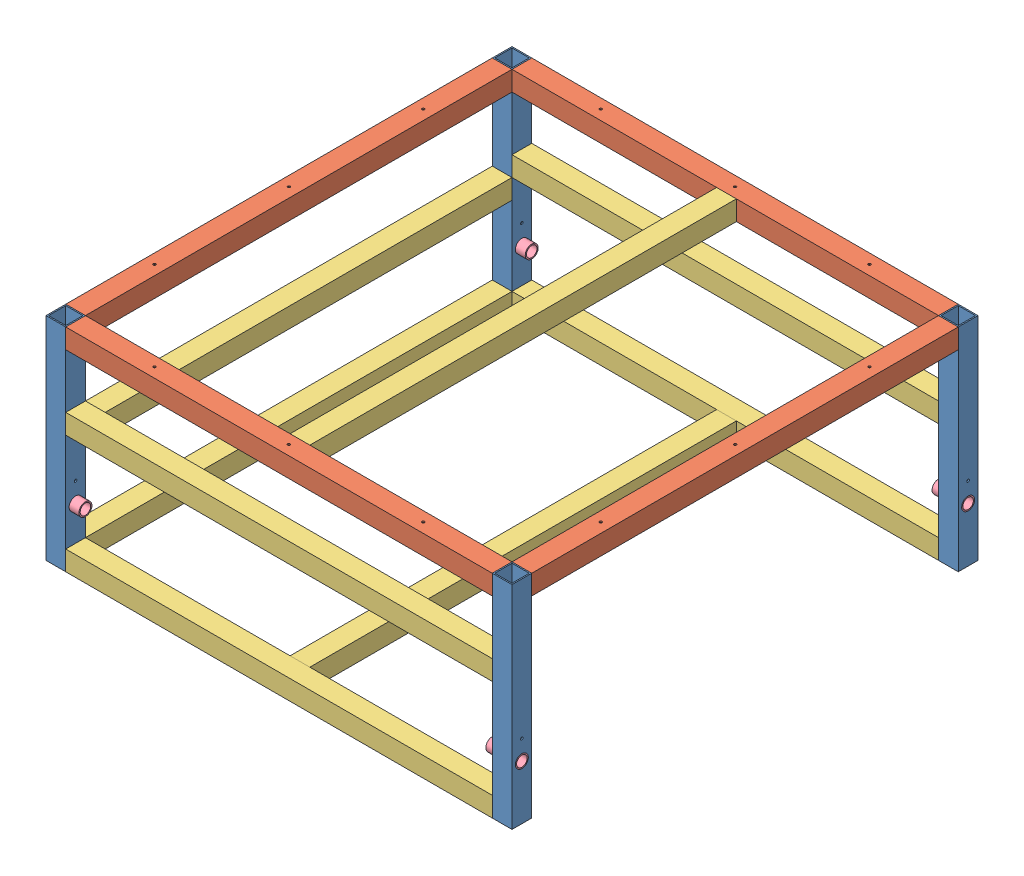
SolidWorks assembly GE-19030, configuration Default. Lengths in mm.
Overall size (1200.15 546.1 1200.15).
20 component instances, 4 part files, 58 mates.
Components (placement in the parent):
- GE-19030-02-1: GE-19030-02 [Default] at (-409.852 -285.75 461.6211) x (-1 0 0) z (0 0 -1) size (50.8 546.1 50.8)
- GE-19030-02-2: GE-19030-02 [Default] at (-409.852 -285.75 1610.9711) x (-1 0 0) z (0 0 -1) size (50.8 546.1 50.8)
- GE-19030-01-2: GE-19030-01 [Default] at (-409.852 -38.1 1036.2961) x (-1 0 0) z (0 0 1) size (50.8 50.8 1098.55)
- GE-19030-01-4: GE-19030-01 [Default] at (-1009.927 -38.1 1636.3711) x (0 0 -1) z (1 0 0) size (50.8 50.8 1098.55)
- GE-19030-01-5: GE-19030-01 [Default] at (-1009.927 -38.1 436.2211) x (0 0 1) z (1 0 0) size (50.8 50.8 1098.55)
- GE-19030-01-9: GE-19030-01 [Default] at (-1610.002 -38.1 1036.2961) size (50.8 50.8 1098.55)
- GE-19030-02-5: GE-19030-02 [Default] at (-1610.002 -285.75 1610.9711) size (50.8 546.1 50.8)
- GE-19030-02-6: GE-19030-02 [Default] at (-1610.002 -285.75 461.6211) size (50.8 546.1 50.8)
- GE-19030-03-5: GE-19030-03 [Default] at (-1584.602 -279.4 487.0211) size (50.8 50.8 1098.55)
- GE-19030-03-6: GE-19030-03 [Default] at (-1006.752 -38.1 487.0211) size (50.8 50.8 1098.55)
- GE-19030-04-1: GE-19030-04 [Default] at (-1610.002 -419.1 1610.9711) x (0 -0.791316 0.611408) z (1 0 0) size (33.4 33.4 76.2)
- GE-19030-04-2: GE-19030-04 [Default] at (-1610.002 -419.1 461.6211) x (0 0 1) z (1 0 0) size (33.4 33.4 76.2)
- GE-19030-04-3: GE-19030-04 [Default] at (-409.852 -419.1 461.6211) x (0 0.9686 0.248623) z (-1 0 0) size (33.4 33.4 76.2)
- GE-19030-04-4: GE-19030-04 [Default] at (-409.852 -419.1 1610.9711) x (0 -0.03489 -0.999391) z (-1 0 0) size (33.4 33.4 76.2)
- GE-19030-03-7: GE-19030-03 [Default] at (-1559.202 -228.6 1610.9711) x (0 0 -1) z (1 0 0) size (50.8 50.8 1098.55)
- GE-19030-03-8: GE-19030-03 [Default] at (-1559.202 -228.6 461.6211) x (0 0 -1) z (1 0 0) size (50.8 50.8 1098.55)
- GE-19030-03-9: GE-19030-03 [Default] at (-1584.602 -533.4 487.0211) size (50.8 50.8 1098.55)
- GE-19030-03-10: GE-19030-03 [Default] at (-1559.202 -533.4 1610.9711) x (0 0 -1) z (1 0 0) size (50.8 50.8 1098.55)
- GE-19030-03-11: GE-19030-03 [Default] at (-1559.202 -533.4 461.6211) x (0 0 -1) z (1 0 0) size (50.8 50.8 1098.55)
- GE-19030-03-12: GE-19030-03 [Default] at (-1006.752 -533.4 487.0211) size (50.8 50.8 1098.55)
Mates (geometry in assembly coordinates):
- Coincident56: coincident: plane of GE-19030-01-4 through (-1559.202 -12.7 1585.5711) normal (-1 0 0); plane of GE-19030-02-5 through (-1559.202 -285.75 1610.9711) normal (1 0 0)
- Coincident57: coincident: plane of GE-19030-01-4 through (-1009.927 -38.1 1636.3711) normal (0 0 1); plane of GE-19030-02-5 through (-1559.202 -558.8 1636.3711) normal (0 0 1)
- Coincident58: coincident: plane of GE-19030-01-4 through (-460.652 -12.7 1585.5711) normal (0 1 0); plane of GE-19030-02-5 through (-1559.202 -12.7 1585.5711) normal (0 1 0)
- Coincident85: coincident: plane of GE-19030-01-9 through (-1559.202 -12.7 1585.5711) normal (0 0 1); plane of GE-19030-02-5 through (-1559.202 -558.8 1585.5711) normal (0 0 -1)
- Coincident86: coincident: plane of GE-19030-01-9 through (-1610.002 -38.1 1036.2961) normal (-1 0 0); plane of GE-19030-02-5 through (-1610.002 -285.75 1610.9711) normal (-1 0 0)
- Coincident87: coincident: plane of GE-19030-01-4 through (-460.652 -12.7 1585.5711) normal (0 1 0); plane of GE-19030-01-9 through (-1559.202 -12.7 1585.5711) normal (0 1 0)
- Coincident111: coincident: plane of GE-19030-02-6 through (-1610.002 -285.75 461.6211) normal (-1 0 0); plane of GE-19030-03-5 through (-1610.002 -304.8 1585.5711) normal (-1 0 0)
- Coincident112: coincident: plane of GE-19030-02-6 through (-1559.202 -558.8 487.0211) normal (0 0 1); plane of GE-19030-03-5 through (-1584.602 -279.4 487.0211) normal (0 0 -1)
- Coincident124: coincident: plane of GE-19030-01-9 through (-1610.002 -38.1 1036.2961) normal (-1 0 0); plane of GE-19030-02-6 through (-1610.002 -285.75 461.6211) normal (-1 0 0)
- Concentric5: concentric: cylinder of GE-19030-02-1 through (-409.852 -419.1 461.6211) axis (-1 0 0) radius 16.7005; cylinder of GE-19030-04-3 through (-486.052 -419.1 461.6211) axis (1 0 0) radius 16.7005
- Coincident131: coincident: plane of GE-19030-02-1 through (-409.852 -285.75 461.6211) normal (1 0 0); plane of GE-19030-04-3 through (-409.852 -419.1 461.6211) normal (1 0 0)
- Concentric6: concentric: cylinder of GE-19030-02-6 through (-1610.002 -419.1 461.6211) axis (1 0 0) radius 16.7005; cylinder of GE-19030-04-2 through (-1533.802 -419.1 461.6211) axis (-1 0 0) radius 16.7005
- Coincident132: coincident: circle of GE-19030-02-6; circle of GE-19030-04-2
- Concentric7: concentric: cylinder of GE-19030-02-5 through (-1610.002 -419.1 1610.9711) axis (1 0 0) radius 16.7005; cylinder of GE-19030-04-1 through (-1533.802 -419.1 1610.9711) axis (-1 0 0) radius 16.7005
- Coincident133: coincident: plane of GE-19030-02-5 through (-1610.002 -285.75 1610.9711) normal (-1 0 0); plane of GE-19030-04-1 through (-1610.002 -419.1 1610.9711) normal (-1 0 0)
- Concentric8: concentric: cylinder of GE-19030-02-2 through (-409.852 -419.1 1610.9711) axis (-1 0 0) radius 16.7005; cylinder of GE-19030-04-4 through (-486.052 -419.1 1610.9711) axis (1 0 0) radius 16.7005
- Coincident134: coincident: plane of GE-19030-02-2 through (-409.852 -285.75 1610.9711) normal (1 0 0); plane of GE-19030-04-4 through (-409.852 -419.1 1610.9711) normal (1 0 0)
- Coincident147: coincident: plane of GE-19030-02-2 through (-460.652 -285.75 1610.9711) normal (-1 0 0); plane of GE-19030-03-7 through (-460.652 -228.6 1610.9711) normal (1 0 0)
- Coincident151: coincident: plane of GE-19030-02-5 through (-1559.202 -558.8 1636.3711) normal (0 0 1); plane of GE-19030-03-7 through (-460.652 -254 1636.3711) normal (0 0 1)
- Coincident152: coincident: plane of GE-19030-03-5 through (-1559.202 -254 1585.5711) normal (0 1 0); plane of GE-19030-03-7 through (-460.652 -254 1585.5711) normal (0 -1 0)
- Coincident153: coincident: plane of GE-19030-02-6 through (-1559.202 -285.75 461.6211) normal (1 0 0); plane of GE-19030-03-8 through (-1559.202 -228.6 461.6211) normal (-1 0 0)
- Coincident154: coincident: plane of GE-19030-02-6 through (-1559.202 -558.8 436.2211) normal (0 0 -1); plane of GE-19030-03-8 through (-460.652 -254 436.2211) normal (0 0 -1)
- Coincident155: coincident: plane of GE-19030-03-5 through (-1559.202 -254 1585.5711) normal (0 1 0); plane of GE-19030-03-8 through (-460.652 -254 436.2211) normal (0 -1 0)
- Parallel2: parallel: plane of GE-19030-02-2 through (-409.852 -285.75 1610.9711) normal (1 0 0); plane of GE-19030-01-2 through (-409.852 -38.1 1036.2961) normal (1 0 0)
- Coincident165: coincident: plane of GE-19030-02-1 through (-409.852 -285.75 461.6211) normal (1 0 0); plane of GE-19030-01-2 through (-409.852 -38.1 1036.2961) normal (1 0 0)
- Distance13: distance = 520.7 mm: plane of GE-19030-01-2 through (-460.652 -38.1 1036.2961) normal (-1 0 0); plane of GE-19030-03-6 through (-981.352 -63.5 1585.5711) normal (1 0 0)
- Coincident168: coincident: plane of GE-19030-01-9 through (-1559.202 -12.7 487.0211) normal (0 0 -1); plane of GE-19030-02-6 through (-1559.202 -558.8 487.0211) normal (0 0 1)
- Coincident174: coincident: line of GE-19030-02-1; line of GE-19030-01-5 through (-460.652 -12.7 487.0211) axis (0 0 -1)
- Coincident175: coincident: line of GE-19030-02-6 through (-1610.002 -12.7 487.0211) axis (0 -1 0); plane of GE-19030-03-9 through (-1584.602 -533.4 487.0211) normal (0 0 -1)
- Coincident176: coincident: plane of GE-19030-02-6 through (-1610.002 -285.75 461.6211) normal (-1 0 0); plane of GE-19030-03-9 through (-1610.002 -558.8 1585.5711) normal (-1 0 0)
- Coincident177: coincident: plane of GE-19030-02-6 through (-1559.202 -558.8 436.2211) normal (0 -1 0); plane of GE-19030-03-9 through (-1559.202 -558.8 1585.5711) normal (0 -1 0)
- Coincident178: coincident: plane of GE-19030-02-5 through (-1559.202 -285.75 1610.9711) normal (1 0 0); plane of GE-19030-03-10 through (-1559.202 -533.4 1610.9711) normal (-1 0 0)
- Coincident179: coincident: plane of GE-19030-03-9 through (-1559.202 -558.8 1585.5711) normal (0 -1 0); plane of GE-19030-03-10 through (-460.652 -558.8 1585.5711) normal (0 -1 0)
- Coincident180: coincident: plane of GE-19030-02-5 through (-1559.202 -558.8 1636.3711) normal (0 0 1); plane of GE-19030-03-10 through (-460.652 -558.8 1636.3711) normal (0 0 1)
- Coincident181: coincident: plane of GE-19030-02-6 through (-1559.202 -285.75 461.6211) normal (1 0 0); plane of GE-19030-03-11 through (-1559.202 -533.4 461.6211) normal (-1 0 0)
- Coincident182: coincident: plane of GE-19030-02-6 through (-1559.202 -558.8 436.2211) normal (0 -1 0); plane of GE-19030-03-11 through (-460.652 -558.8 436.2211) normal (0 -1 0)
- Coincident183: coincident: plane of GE-19030-02-6 through (-1559.202 -558.8 436.2211) normal (0 0 -1); plane of GE-19030-03-11 through (-460.652 -558.8 436.2211) normal (0 0 -1)
- Coincident188: coincident: plane of GE-19030-02-1 through (-460.652 -285.75 461.6211) normal (-1 0 0); plane of GE-19030-03-11 through (-460.652 -533.4 461.6211) normal (1 0 0)
- Coincident191: coincident: plane of GE-19030-01-5 through (-460.652 -12.7 487.0211) normal (0 1 0); plane of GE-19030-02-6 through (-1559.202 -12.7 436.2211) normal (0 1 0)
- Coincident192: coincident: plane of GE-19030-01-5 through (-1009.927 -38.1 436.2211) normal (0 0 -1); plane of GE-19030-02-6 through (-1559.202 -558.8 436.2211) normal (0 0 -1)
- Coincident193: coincident: plane of GE-19030-02-1 through (-460.652 -558.8 436.2211) normal (0 0 -1); plane of GE-19030-01-5 through (-1009.927 -38.1 436.2211) normal (0 0 -1)
- Coincident194: coincident: plane of GE-19030-02-1 through (-460.652 -558.8 487.0211) normal (0 0 1); line of GE-19030-01-2 through (-413.027 -15.875 487.0211) axis (-1 0 0)
- Coincident195: coincident: plane of GE-19030-02-1 through (-460.652 -12.7 487.0211) normal (0 1 0); plane of GE-19030-01-2 through (-460.652 -12.7 1585.5711) normal (0 1 0)
- Coincident196: coincident: plane of GE-19030-01-9 through (-1559.202 -12.7 1585.5711) normal (0 1 0); plane of GE-19030-02-6 through (-1559.202 -12.7 436.2211) normal (0 1 0)
- Coincident197: coincident: plane of GE-19030-02-2 through (-460.652 -285.75 1610.9711) normal (-1 0 0); plane of GE-19030-01-4 through (-460.652 -12.7 1585.5711) normal (1 0 0)
- Coincident198: coincident: plane of GE-19030-02-2 through (-460.652 -558.8 1585.5711) normal (0 0 -1); plane of GE-19030-01-2 through (-460.652 -63.5 1585.5711) normal (0 0 1)
- Coincident199: coincident: plane of GE-19030-02-2 through (-460.652 -558.8 1636.3711) normal (0 -1 0); plane of GE-19030-03-10 through (-460.652 -558.8 1585.5711) normal (0 -1 0)
- Distance14: distance = 254 mm: plane of GE-19030-03-8 through (-460.652 -254 436.2211) normal (0 -1 0); plane of GE-19030-03-11 through (-460.652 -508 436.2211) normal (0 1 0)
- Coincident201: coincident: plane of GE-19030-01-5 through (-1009.927 -38.1 487.0211) normal (0 0 1); plane of GE-19030-03-6 through (-1006.752 -38.1 487.0211) normal (0 0 -1)
- Coincident204: coincident: plane of GE-19030-03-6 through (-981.352 -63.5 1585.5711) normal (1 0 0); plane of GE-19030-03-12 through (-981.352 -558.8 1585.5711) normal (1 0 0)
- Coincident205: coincident: plane of GE-19030-03-10 through (-460.652 -558.8 1585.5711) normal (0 -1 0); plane of GE-19030-03-12 through (-981.352 -558.8 1585.5711) normal (0 -1 0)
- Coincident206: coincident: plane of GE-19030-03-10 through (-460.652 -558.8 1585.5711) normal (0 0 -1); plane of GE-19030-03-12 through (-1006.752 -533.4 1585.5711) normal (0 0 1)
- Coincident211: coincident: plane of GE-19030-02-2 through (-460.652 -12.7 1636.3711) normal (0 1 0); plane of GE-19030-01-2 through (-460.652 -12.7 1585.5711) normal (0 1 0)
- Coincident212: coincident: line of GE-19030-01-5 through (-460.652 -12.7 436.2211) axis (-1 0 0); plane of GE-19030-03-6 through (-981.352 -12.7 1585.5711) normal (0 1 0)
- Distance15: distance = 9.525 mm: plane of ? through (-1009.927 0 1645.8961) normal (0 0 1); plane of GE-19030-01-4 through (-1009.927 -38.1 1636.3711) normal (0 0 1)
- Distance16: distance = 9.525 mm: plane of ? through (-400.327 0 1620.4961) normal (1 0 0); plane of GE-19030-01-2 through (-409.852 -38.1 1036.2961) normal (1 0 0)
- Coincident219: coincident: plane of GE-19030-01-4 through (-460.652 -12.7 1585.5711) normal (0 1 0); plane of ? through (-1009.927 -12.7 1620.4961) normal (0 -1 0)
- Coincident220: coincident: plane of ? through (-1009.927 0 1620.4961) normal (0 1 0); plane of assembly through (0 0 0) normal (0 1 0)
